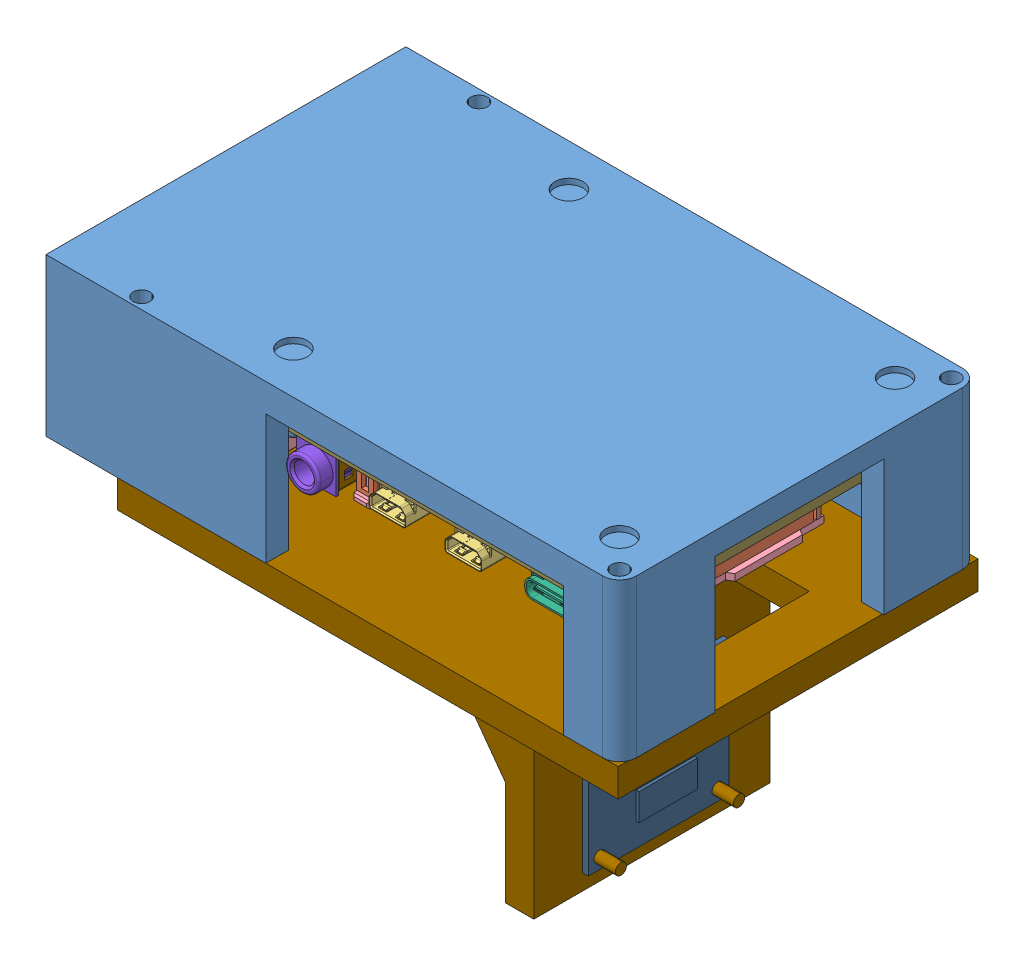
SolidWorks assembly assembly, configuration Default. Lengths in mm.
Overall size (102 70 64).
37 component instances, 28 part files, 9 mates.
Components (placement in the parent):
- Housing-1: Housing [Default] at (-48.6898 24.326 20.894) size (102 28 64)
- Assembly Raspberry Pi 4 Model B step.STEP-1: Assembly Raspberry Pi 4 Model B step.STEP [Default] at (-175.3804 104.526 17.7758) x (-1 0 0) z (0 -1 0) size (89.07 58.45 20.84)
  - Display connector assembly.STEP-1: Display connector assembly.STEP [Default] at (-175.8005 -4.9769 88.3803) x (0 1 0) z (1 0 0) size (22.4 5.68 5.12)
    - 2.2 part 2 with combine.STEP-1: 2.2 part 2 with combine.STEP [Default] at (1.8587 0.0697 19.1) size (20.6 5.3 3)
    - 1.1 part 1 metal pin.STEP-1: 1.1 part 1 metal pin.STEP [Default] at (-5.0213 -2.5803 20.6021) x (0 0 1) z (-1 0 0) size (4.82 4.69 14.25)
    - 3.3 plastic.STEP-1: 3.3 plastic.STEP [Default] at (1.8587 1.7197 20.05) x (-1 0 0) z (0 1 0) size (22.4 3.9 5.18)
  - Display connector assembly-1.STEP-1: Display connector assembly-1.STEP [Default] at (-133.2905 -21.4369 88.3803) x (0 1 0) z (1 0 0) size (22.4 5.68 5.12)
    - 2.2 part 2 with combine.STEP-1: 2.2 part 2 with combine.STEP [Default] at (1.8587 0.0697 19.1) size (20.6 5.3 3)
    - 1.1 part 1 metal pin.STEP-1: 1.1 part 1 metal pin.STEP [Default] at (-5.0213 -2.5803 20.6021) x (0 0 1) z (-1 0 0) size (4.82 4.69 14.25)
    - 3.3 plastic.STEP-1: 3.3 plastic.STEP [Default] at (1.8587 1.7197 20.05) x (-1 0 0) z (0 1 0) size (22.4 3.9 5.18)
  - Card slot assembly.STEP-1: Card slot assembly.STEP [Default] at (-161.3453 3.4611 71.49) x (0 1 0) z (0 0 1) size (11.95 11.4 1.48)
    - card slot part 2 metal pin.STEP-1: card slot part 2 metal pin.STEP [Default] at (-3.5293 -7.6678 12.2938) x (0 -1 0) z (1 0 0) size (7.95 0.89 8.04)
    - sd card slot v1.STEP-1: sd card slot v1.STEP [Default] at (-18.1743 -9.7848 12.71) x (-1 0 0) z (0 0 -1) size (11.71 10.28 1.3)
    - part 3 v1.STEP-1: part 3 v1.STEP [Default] at (-6.4643 -9.3448 11.38) x (1 0 0) z (0 0 -1) size (11.95 11.4 1.45)
  - Microphone plug assembly.STEP-1: Microphone plug assembly.STEP [Default] at (-98.1635 -39.0194 79.6496) x (-1 0 0) z (0 1 0) size (7.23 7.55 15)
    - part 4 microphone plug.STEP-1: part 4 microphone plug.STEP [Default] at (7.027 9.1504 5.4512) size (7 6.8 15)
    - Microphone plug part 1.STEP-1: Microphone plug part 1.STEP [Default] at (7.027 11.4504 8.5512) x (-1 0 0) z (0 1 0) size (7.23 9.23 7.2)
    - part 2 microphon plug metal.STEP-1: part 2 microphon plug metal.STEP [Default] at (5.712 4.6004 12.1798) x (-1 0 0) z (0 1 0) size (6.87 8.22 7.3)
    - part 3 microphone plug.STEP-1: part 3 microphone plug.STEP [Default] at (7.042 6.6004 17.8712) x (-1 0 0) z (0 1 0) size (3.2 10.71 4.14)
  - 1.0 Plate raspberry Pi 4.STEP-1: 1.0 Plate raspberry Pi 4.STEP [Default] at (-116.6905 -3.1182 84.2) size (85 56 1.7)
  - 2.0. PIN HEADER  one.STEP-1: 2.0. PIN HEADER  one.STEP [Default] at (-97.6861 15.3918 88.3) size (5.08 5.08 11.8)
  - 3.0 PIN HEADER 20.STEP-1: 3.0 PIN HEADER 20.STEP [Default] at (-103.8305 21.3818 88.3) x (0 -1 0) z (0 0 1) size (5.08 50.8 11.8)
  - 4.0 metal plate..STEP-1: 4.0 metal plate..STEP [Default] at (-147.1905 11.3818 87.2) x (-1 0 0) z (0 0 1) size (11.01 13.01 1.6)
  - 5.0 CPU Broadcom.STEP-1: 5.0 CPU Broadcom.STEP [Default] at (-129.9505 1.4218 85.8) size (15 15 2.3)
  - 6.0 9FD77 D9WHV.STEP-1: 6.0 9FD77 D9WHV.STEP [Default] at (-114.4505 1.4218 85.8) size (10 14.5 0.8)
  - 7.0 MxL.STEP-1: 7.0 MxL.STEP [Default] at (-149.2005 -19.0782 85.8) size (5.48 5.48 0.9)
  - 8.0 Gigabit Ethernet Transceiver.STEP-1: 8.0 Gigabit Ethernet Transceiver.STEP [Default] at (-100.2005 6.9218 85.8) size (6.9 6.9 1.1)
  - 9.0 VLI PCIe USB 3.0 Controller.STEP-1: 9.0 VLI PCIe USB 3.0 Controller.STEP [Default] at (-99.2005 -7.0782 85.8) x (0 1 0) z (0 0 1) size (8.9 8.9 0.9)
  - 11.0 Female micro HDMI connector.STEP-1: 11.0 Female micro HDMI connector.STEP [Default] at (-133.2005 -25.4082 87.25) x (1 0 0) z (0 -1 0) size (6.5 3.51 7.5)
  - 11.0 Female micro HDMI connector.STEP-2: 11.0 Female micro HDMI connector.STEP [Default] at (-119.7005 -25.4082 87.25) x (1 0 0) z (0 -1 0) size (6.5 3.51 7.5)
  - 15.0   2x USB 2.0 PORT.STEP-1: 15.0   2x USB 2.0 PORT.STEP [Default] at (-87.9805 -22.0582 93.6) x (0 0 1) z (1 0 0) size (19.16 15.33 17.86)
  - 14.0  2x USB 3.0 PORT.STEP-1: 14.0  2x USB 3.0 PORT.STEP [Default] at (-88.0505 -4.0182 94.78) x (0 0 1) z (1 0 0) size (20.65 15.33 17.87)
  - 10.0 Female USB connector.STEP-1: 10.0 Female USB connector.STEP [Default] at (-147.9905 -24.6982 87.38) x (1 0 0) z (0 -1 0) size (8.94 3.96 7.9)
  - 12.0 Gigabit ethernet port raspberry.STEP-1: 12.0 Gigabit ethernet port raspberry.STEP [Default] at (-71.1905 14.6318 92.725) x (0 1 0) z (1 0 0) size (16.1 17.2 21.45)
  - 9.0 VLI PCIe USB 3.0 Controller v1.STEP-1: 9.0 VLI PCIe USB 3.0 Controller v1.STEP [Default] at (-99.1805 -7.0982 85.8092) size (8.9 8.9 0.9)
- top-1: top [Default] at (-56.9398 0.326 20.894) x (1 0 0) z (0 0 -1) size (89 42 64)
- rasberrypi_v2_camera-1: rasberrypi_v2_camera [Varsayılan] at (-38.2398 -38.674 8.394) x (0 0 1) z (1 0 0) size (25 34 3.2)
Mates (geometry in assembly coordinates):
- Concentric2: concentric aligned: cylinder of Housing-1 through (-19.6898 27.326 -3.606) axis (0 -1 0) radius 1.35; cylinder of Assembly Raspberry Pi 4 Model B step.STEP-1/1.0 Plate raspberry Pi 4.STEP-1 through (-19.6898 20.426 -3.606) axis (0 -1 0) radius 1.3
- Concentric3: concentric aligned: cylinder of Housing-1 through (-19.6898 27.326 45.394) axis (0 -1 0) radius 1.35; cylinder of Assembly Raspberry Pi 4 Model B step.STEP-1/1.0 Plate raspberry Pi 4.STEP-1 through (-19.6898 20.426 45.394) axis (0 -1 0) radius 1.35
- Coincident1: coincident anti-aligned: plane of Housing-1 through (-48.6898 20.326 20.894) normal (0 -1 0); plane of Assembly Raspberry Pi 4 Model B step.STEP-1/1.0 Plate raspberry Pi 4.STEP-1 through (-19.1898 20.326 45.894) normal (0 1 0)
- Concentric8: concentric anti-aligned: cylinder of Housing-1 through (-14.6898 28.326 50.394) axis (0 -1 0) radius 1.5; cylinder of top-1 through (-14.6898 -4.674 50.394) axis (0 1 0) radius 1.5
- Concentric9: concentric anti-aligned: cylinder of Housing-1 through (-14.6898 28.326 -8.606) axis (0 -1 0) radius 1.5; cylinder of top-1 through (-14.6898 -4.674 -8.606) axis (0 1 0) radius 1.5
- Coincident3: coincident anti-aligned: plane of Housing-1 through (-48.6898 0.326 20.894) normal (0 -1 0); plane of top-1 through (-56.9398 0.326 20.894) normal (0 1 0)
- Concentric11: concentric aligned: cylinder of top-1 through (-33.4398 -36.674 31.394) axis (-1 0 0) radius 0.99; cylinder of rasberrypi_v2_camera-1 through (-37.2398 -36.674 31.394) axis (-1 0 0) radius 1
- Concentric12: concentric aligned: cylinder of top-1 through (-33.4398 -36.674 10.394) axis (-1 0 0) radius 0.99; cylinder of rasberrypi_v2_camera-1 through (-37.2398 -36.674 10.394) axis (-1 0 0) radius 1
- Coincident5: coincident anti-aligned: plane of top-1 through (-38.4398 -41.674 41.894) normal (1 0 0); plane of rasberrypi_v2_camera-1 through (-38.4398 -38.674 8.394) normal (-1 0 0)
